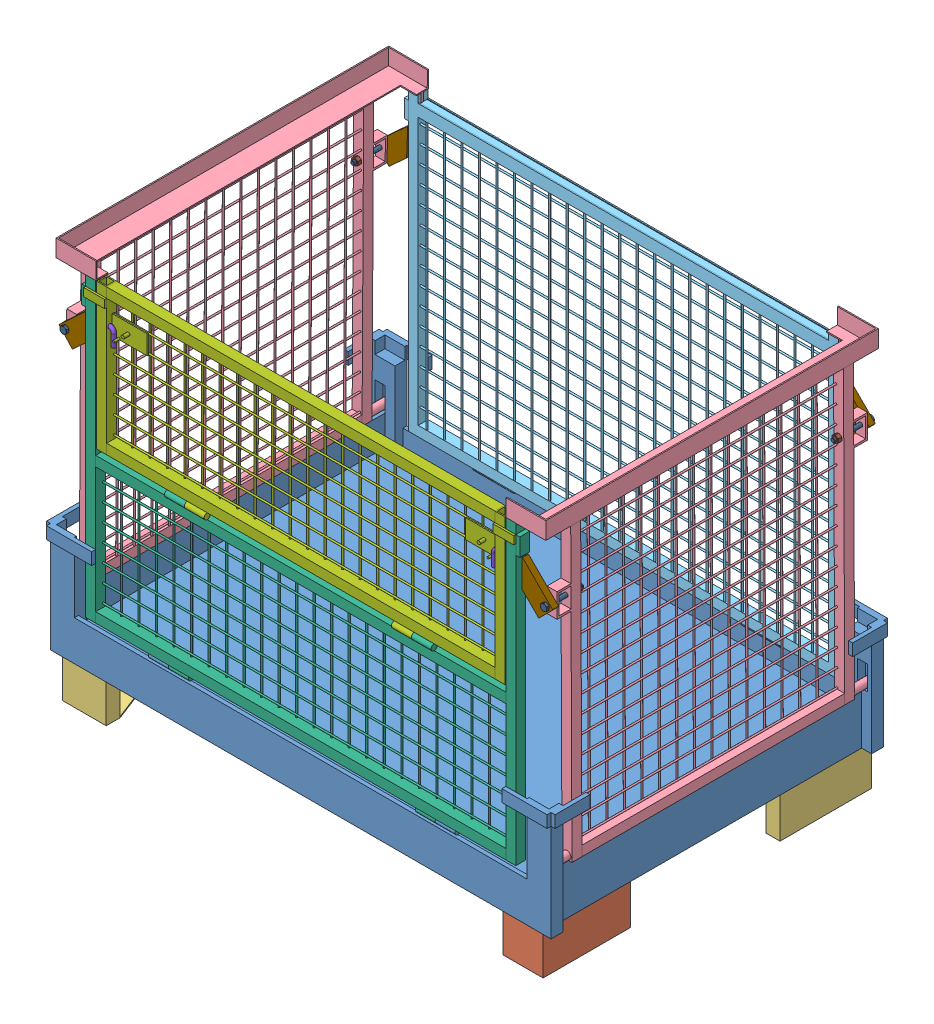
SolidWorks assembly Gabbia legna_2, configuration Default. Lengths in mm.
Overall size (1277 1003.06 855).
25 component instances, 11 part files, 45 mates.
Components (placement in the parent):
- Base-1: Base [Default] at origin size (1277 275 855)
- Piede gabbia-1: Piede gabbia [Default] at (603.5 -100 412.5) size (100 100 220)
- Piede gabbia-3: Piede gabbia [Default] at (-603.5 -100 -412.5) x (-1 0 0) z (0 0 -1) size (100 100 220)
- Piede gabbia 2-1: Piede gabbia 2 [Default] at (-598.5 -100 407.5) size (110 100 230)
- Piede gabbia 2-2: Piede gabbia 2 [Default] at (598.5 -100 -407.5) x (-1 0 0) z (0 0 -1) size (110 100 230)
- Parte laterale-1: Parte laterale [Default] at (615.4552 860.0464 0) x (0 0 -1) z (0.999991 0.004229 0) size (835 773 100)
- Parte posteriore-1: Parte posteriore [Default] at (0 115 -405) x (-1 0 0) z (0 0 -1) size (1100 760 25)
- Assieme porta anteriore-1: Assieme porta anteriore [Default] at (25 495 415) size (1100 760 32.5)
  - Parte anteriore-1: Parte anteriore [Default] at (-25 -380 -10) size (1100 760 32.5)
  - Porta parte anteriore-3: Porta parte anteriore [Default] at (-25 0 -10) size (1080 380 32.5)
  - Fermo porta parte anteriore-1: Fermo porta parte anteriore [Default] at (-561.5 276 -5.5) size (64 45 10)
  - Fermo porta parte anteriore-2: Fermo porta parte anteriore [Default] at (511.5 276 -5.5) x (-1 0 0) z (0 0 -1) size (64 45 10)
- Parte laterale-2: Parte laterale [Default] at (-614.3712 860.0598 0) x (0 0 1) z (-0.999984 0.005734 0) size (835 773 100)
- Fermo laterale-1: Fermo laterale [Default] at (620.5813 704.9949 390) x (0.707107 0.707107 0) z (0 0 1) size (50 108.59 15)
- Fermo laterale-2: Fermo laterale [Default] at (620.5813 704.9949 -405) x (0.707107 0.707107 0) z (0 0 1) size (50 108.59 15)
- Fermo laterale-5: Fermo laterale [Default] at (-619.7168 705.6802 405) x (-0.677793 0.735252 0) z (0 0 -1) size (50 108.59 15)
- Fermo laterale-6: Fermo laterale [Default] at (-619.7168 705.6802 -390) x (-0.677793 0.735252 0) z (0 0 -1) size (50 108.59 15)
- hex bolt gradeab_iso-2: hex bolt gradeab_iso [ISO 4014 - M10 x 90 x 26-N] at (603.6108 704.9949 411.4) x (0 0 -1) z (1 0 0) size (96.4 18.48 16)
- hex bolt gradeab_iso-3: hex bolt gradeab_iso [ISO 4014 - M10 x 90 x 26-N] at (603.6108 704.9949 -411.4) x (0 0 1) z (-1 0 0) size (96.4 18.48 16)
- hex bolt gradeab_iso-4: hex bolt gradeab_iso [ISO 4014 - M10 x 90 x 26-N] at (-602.7602 704.9907 -411.4) x (0 0 1) z (-1 0 0) size (96.4 18.48 16)
- hex bolt gradeab_iso-5: hex bolt gradeab_iso [ISO 4014 - M10 x 90 x 26-N] at (-602.7602 704.9907 411.4) x (0 0 -1) z (1 0 0) size (96.4 18.48 16)
- hex nut gradec_iso-2: hex nut gradec_iso [ISO - 4034 - M10 - N] at (-602.7602 704.9907 320.5) x (0.923728 0.383049 0) z (0 0 -1) size (16 18.48 9.5)
- hex nut gradec_iso-3: hex nut gradec_iso [ISO - 4034 - M10 - N] at (-602.7602 704.9907 -320.5) size (16 18.48 9.5)
- hex nut gradec_iso-4: hex nut gradec_iso [ISO - 4034 - M10 - N] at (603.6108 704.9949 -320.5) size (16 18.48 9.5)
- hex nut gradec_iso-5: hex nut gradec_iso [ISO - 4034 - M10 - N] at (603.6108 704.9949 320.5) x (0.923728 0.383049 0) z (0 0 -1) size (16 18.48 9.5)
Mates (geometry in assembly coordinates):
- Coincidente1: coincident anti-aligned: plane of Base-1 through (0 0 0) normal (0 -1 0); plane of Piede gabbia-1 through (603.5 0 412.5) normal (0 1 0)
- Coincidente2: coincident aligned: plane of Base-1 through (603.5 100 417.5) normal (1 0 0); plane of Piede gabbia-1 through (603.5 0 412.5) normal (1 0 0)
- Coincidente3: coincident aligned: plane of Piede gabbia-1 through (508.5 0 407.5) normal (0 0 -1); plane of Base-1 through (-603.5 100 407.5) normal (0 0 -1)
- Coincidente6: coincident aligned: plane of Base-1 through (-603.5 100 417.5) normal (-1 0 0); plane of Piede gabbia-3 through (-603.5 0 -412.5) normal (-1 0 0)
- Coincidente7: coincident aligned: plane of Piede gabbia-3 through (-508.5 0 -407.5) normal (0 0 1); plane of Base-1 through (-603.5 100 -407.5) normal (0 0 1)
- Coincidente8: coincident anti-aligned: plane of Base-1 through (0 0 0) normal (0 -1 0); plane of Piede gabbia-3 through (-603.5 0 -412.5) normal (0 1 0)
- Coincidente9: coincident aligned: plane of Base-1 through (-603.5 100 407.5) normal (0 0 -1); plane of Piede gabbia 2-1 through (-498.5 0 407.5) normal (0 0 -1)
- Coincidente10: coincident aligned: plane of Base-1 through (-603.5 100 417.5) normal (-1 0 0); plane of Piede gabbia 2-1 through (-603.5 0 412.5) normal (-1 0 0)
- Coincidente11: coincident anti-aligned: plane of Base-1 through (0 0 0) normal (0 -1 0); plane of Piede gabbia 2-1 through (-598.5 0 407.5) normal (0 1 0)
- Coincidente12: coincident aligned: plane of Base-1 through (-603.5 100 -407.5) normal (0 0 1); plane of Piede gabbia 2-2 through (498.5 0 -407.5) normal (0 0 1)
- Coincidente13: coincident aligned: plane of Base-1 through (603.5 100 417.5) normal (1 0 0); plane of Piede gabbia 2-2 through (603.5 0 -412.5) normal (1 0 0)
- Coincidente14: coincident anti-aligned: plane of Base-1 through (0 0 0) normal (0 -1 0); plane of Piede gabbia 2-2 through (598.5 0 -407.5) normal (0 1 0)
- Larghezza1: width: plane of Base-1 through (-603.5 100 417.5) normal (0 0 1); plane of Parte laterale-1 through (-603.5 100 -417.5) normal (0 0 -1); plane of Base-1 through (618.5422 130.0529 -355) normal (0 0 -1); plane of Parte laterale-1 through (618.5422 130.0529 355) normal (0 0 1)
- Cardine1: hinge = 1.570796 rad anti-aligned: cylinder of Base-1 through (385 107.5 -407.5) axis (-1 0 0) radius 7.5; cylinder of Base-1 through (285 107.5 -407.5) axis (1 0 0) radius 7.5; plane of Parte posteriore-1 through (335 107.5 -407.5) normal (-1 0 0); plane of Parte posteriore-1 through (335 107.5 -407.5) normal (1 0 0); plane of Base-1 through (-603.5 55 -500000) normal (0 1 0); plane of Parte posteriore-1 through (540 860 -392.5) normal (0 0 1)
- Cardine2: hinge = 4.712389 rad anti-aligned: cylinder of Base-1 through (-385 107.5 407.5) axis (1 0 0) radius 7.5; cylinder of Base-1 through (-285 107.5 407.5) axis (-1 0 0) radius 7.5; plane of Assieme porta anteriore-1/Parte anteriore-1 through (-335 107.5 407.5) normal (1 0 0); plane of Base-1 through (-335 107.5 407.5) normal (-1 0 0); plane of Assieme porta anteriore-1/Parte anteriore-1 through (540 860 392.5) normal (0 0 -1); plane of Assieme porta anteriore-1/Parte anteriore-1 through (-603.5 55 -500000) normal (0 1 0)
- AngoloLimite2: limit planar angle = 1.566568 rad anti-aligned: plane of Base-1 through (-603.5 55 -500000) normal (0 1 0); plane of Parte laterale-1 through (593.5424 129.9472 355) normal (-0.999991 -0.004229 0)
- Larghezza2: width: plane of Base-1 through (618.5 0 0) normal (-1 0 0); plane of Parte laterale-1 through (593.5 195 -387.5) normal (1 0 0); cylinder of Base-1 through (606 140 -407.5) axis (0 0 1) radius 10
- Tangente1: tangent anti-aligned: plane of Base-1 through (0 130 0) normal (0 1 0); cylinder of Parte laterale-1 through (606 140 -407.5) axis (0 0 1) radius 10
- Tangente2: tangent anti-aligned: plane of Base-1 through (0 130 0) normal (0 1 0); cylinder of Parte laterale-2 through (-606 140 407.5) axis (0 0 -1) radius 10
- Larghezza3: width: plane of Base-1 through (-618.5 0 0) normal (1 0 0); plane of Parte laterale-2 through (-593.5 195 387.5) normal (-1 0 0); cylinder of Base-1 through (-606 140 407.5) axis (0 0 -1) radius 10
- Larghezza4: width: plane of Base-1 through (-603.5 100 -417.5) normal (0 0 -1); plane of Parte laterale-2 through (-603.5 100 417.5) normal (0 0 1); plane of Base-1 through (-618.5571 130.0718 -355) normal (0 0 -1); plane of Parte laterale-2 through (-618.5571 130.0718 355) normal (0 0 1)
- AngoloLimite3: limit planar angle = 1.565062 rad anti-aligned: plane of Base-1 through (-603.5 55 -500000) normal (0 1 0); plane of Parte laterale-2 through (-593.5575 129.9285 355) normal (0.999984 -0.005734 0)
- Larghezza5: width: plane of Base-1 through (-603.5 100 417.5) normal (0 0 1); plane of Parte laterale-1 through (-603.5 100 -417.5) normal (0 0 -1); plane of Base-1 through (618.5422 130.0529 355) normal (0 0 1); plane of Parte laterale-1 through (618.5422 130.0529 -355) normal (0 0 -1)
- Concentrico1: concentric anti-aligned: cylinder of Parte laterale-1 through (603.6108 704.9949 315.8579) axis (0 0 1) radius 5; cylinder of Fermo laterale-1 through (603.6108 704.9949 405) axis (0 0 -1) radius 5
- Coincidente15: coincident anti-aligned: plane of Parte laterale-1 through (521.5224 734.6481 390) normal (0 0 1); plane of Fermo laterale-1 through (620.5813 704.9949 390) normal (0 0 -1)
- AngoloLimite4: limit planar angle = 0.781169 rad aligned: plane of Fermo laterale-1 through (620.5813 704.9949 405) normal (0.707107 0.707107 0); plane of Parte laterale-1 through (618.5422 130.0529 355) normal (0.999991 0.004229 0)
- Concentrico2: concentric aligned: cylinder of Parte laterale-2 through (-602.7602 704.9907 315.8579) axis (0 0 1) radius 5; cylinder of Fermo laterale-5 through (-602.7602 704.9907 390) axis (0 0 1) radius 5
- Coincidente16: coincident anti-aligned: plane of Parte laterale-2 through (-520.6273 734.5202 390) normal (0 0 1); plane of Fermo laterale-5 through (-619.7168 705.6802 390) normal (0 0 -1)
- AngoloLimite5: limit planar angle = 0.820305 rad aligned: plane of Parte laterale-2 through (-618.5571 130.0718 355) normal (-0.999984 0.005734 0); plane of Fermo laterale-5 through (-619.7168 705.6802 390) normal (-0.677793 0.735252 0)
- Concentrico3: concentric anti-aligned: cylinder of Fermo laterale-1 through (603.6108 704.9949 405) axis (0 0 -1) radius 5; cylinder of hex bolt gradeab_iso-2 through (603.6108 704.9949 411.4) axis (0 0 1) radius 8
- Coincidente18: coincident anti-aligned: plane of Fermo laterale-1 through (620.5813 704.9949 405) normal (0 0 1); plane of hex bolt gradeab_iso-2 through (603.6108 714.2326 405) normal (0 0 -1)
- Concentrico4: concentric aligned: cylinder of Fermo laterale-2 through (603.6108 704.9949 -390) axis (0 0 -1) radius 5; cylinder of hex bolt gradeab_iso-3 through (603.6108 704.9949 -411.4) axis (0 0 -1) radius 8
- Coincidente19: coincident anti-aligned: plane of Fermo laterale-2 through (620.5813 704.9949 -405) normal (0 0 -1); plane of hex bolt gradeab_iso-3 through (603.6108 714.2326 -405) normal (0 0 1)
- Concentrico5: concentric anti-aligned: cylinder of Fermo laterale-6 through (-602.7602 704.9907 -405) axis (0 0 1) radius 5; cylinder of hex bolt gradeab_iso-4 through (-602.7602 704.9907 -411.4) axis (0 0 -1) radius 8
- Coincidente20: coincident anti-aligned: plane of Fermo laterale-6 through (-619.7168 705.6802 -405) normal (0 0 -1); plane of hex bolt gradeab_iso-4 through (-602.7602 714.2283 -405) normal (0 0 1)
- Concentrico6: concentric aligned: cylinder of Fermo laterale-5 through (-602.7602 704.9907 390) axis (0 0 1) radius 5; cylinder of hex bolt gradeab_iso-5 through (-602.7602 704.9907 411.4) axis (0 0 1) radius 8
- Coincidente21: coincident anti-aligned: plane of Fermo laterale-5 through (-619.7168 705.6802 405) normal (0 0 1); plane of hex bolt gradeab_iso-5 through (-602.7602 714.2283 405) normal (0 0 -1)
- Concentrico7: concentric anti-aligned: cylinder of Parte laterale-2 through (-602.7602 704.9907 315.8579) axis (0 0 1) radius 5; cylinder of hex nut gradec_iso-2 through (-602.7602 704.9907 345.5375) axis (0 0 -1) radius 5
- Coincidente22: coincident anti-aligned: plane of Parte laterale-2 through (-618.5571 130.0718 330) normal (0 0 -1); plane of hex nut gradec_iso-2 through (-599.2218 696.4577 330) normal (0 0 1)
- Concentrico8: concentric anti-aligned: cylinder of Parte laterale-2 through (-602.7602 704.9907 -315.8579) axis (0 0 -1) radius 5; cylinder of hex nut gradec_iso-3 through (-602.7602 704.9907 -345.5375) axis (0 0 1) radius 5
- Coincidente23: coincident anti-aligned: plane of Parte laterale-2 through (-618.5571 130.0718 -330) normal (0 0 1); plane of hex nut gradec_iso-3 through (-602.7602 714.2283 -330) normal (0 0 -1)
- Concentrico9: concentric anti-aligned: cylinder of Parte laterale-1 through (603.6108 704.9949 -315.8579) axis (0 0 -1) radius 5; cylinder of hex nut gradec_iso-4 through (603.6108 704.9949 -345.5375) axis (0 0 1) radius 5
- Coincidente24: coincident anti-aligned: plane of Parte laterale-1 through (618.5422 130.0529 -330) normal (0 0 1); plane of hex nut gradec_iso-4 through (603.6108 714.2326 -330) normal (0 0 -1)
- Concentrico10: concentric anti-aligned: cylinder of Parte laterale-1 through (603.6108 704.9949 315.8579) axis (0 0 1) radius 5; cylinder of hex nut gradec_iso-5 through (603.6108 704.9949 345.5375) axis (0 0 -1) radius 5
- Coincidente25: coincident anti-aligned: plane of Parte laterale-1 through (618.5422 130.0529 330) normal (0 0 -1); plane of hex nut gradec_iso-5 through (607.1492 696.4619 330) normal (0 0 1)
